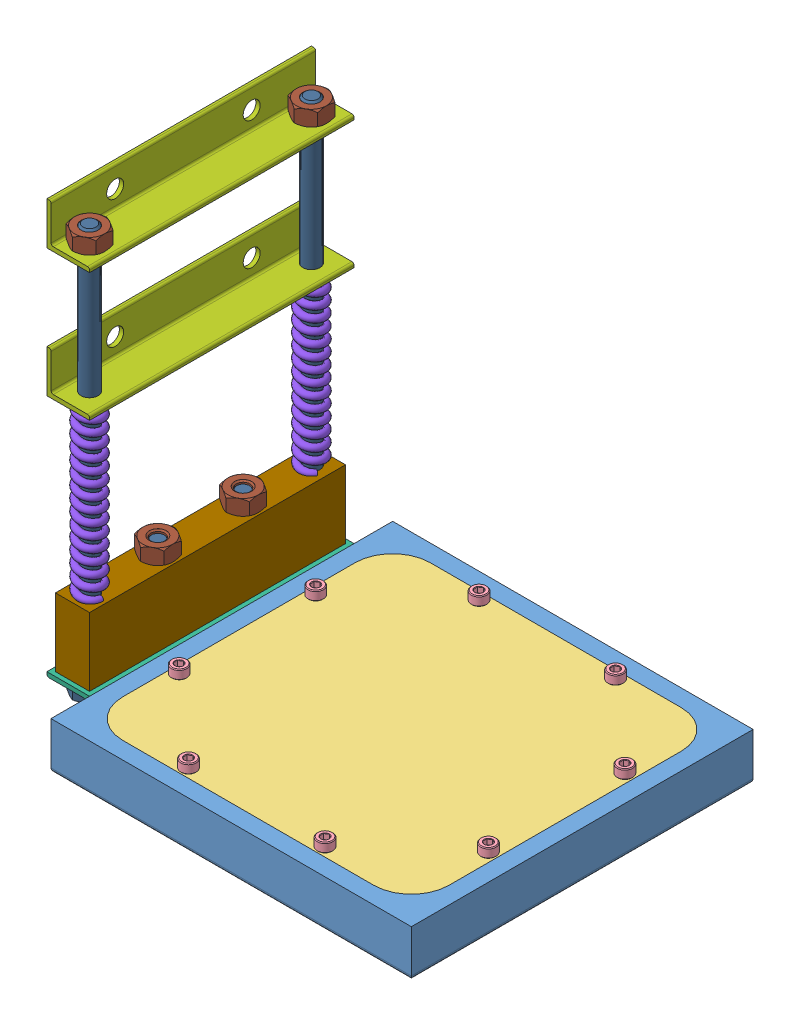
SolidWorks assembly SensorAssembly.1.11.2021, configuration Default. Lengths in mm.
Overall size (150.39 309.5 174.45).
28 component instances, 11 part files, 48 mates.
Components (placement in the parent):
- NDE Sensor Mount Assembly-2: NDE Sensor Mount Assembly [Default] at (58.3304 -65.2661 8.9552) size (134.11 22.72 127.15)
  - CaseBody-1: CaseBody [Default] at origin size (134.11 17.46 127.15)
  - WearPlateAndMount-1: WearPlateAndMount [Default] at (0 3.175 0) size (108.71 3.17 101.75)
  - Cover Plate-1: Cover Plate [Default] at (0 15.875 0) size (121.41 3.17 114.45)
  - 97334A146_NYLON SOCKET HEAD CAP SCREW-1: 97334A146_NYLON SOCKET HEAD CAP SCREW [97334A146] at (-57.531 9.525 -25.4) x (1 0 0) z (0 -1 0) size (5.74 5.74 13.88)
  - 97334A146_NYLON SOCKET HEAD CAP SCREW-2: 97334A146_NYLON SOCKET HEAD CAP SCREW [97334A146] at (-57.531 9.525 25.4) x (1 0 0) z (0 -1 0) size (5.74 5.74 13.88)
  - 97334A146_NYLON SOCKET HEAD CAP SCREW-3: 97334A146_NYLON SOCKET HEAD CAP SCREW [97334A146] at (-25.4 9.525 54.0512) x (1 0 0) z (0 -1 0) size (5.74 5.74 13.88)
  - 97334A146_NYLON SOCKET HEAD CAP SCREW-4: 97334A146_NYLON SOCKET HEAD CAP SCREW [97334A146] at (-25.4 9.525 -54.0512) x (1 0 0) z (0 -1 0) size (5.74 5.74 13.88)
  - 97334A146_NYLON SOCKET HEAD CAP SCREW-5: 97334A146_NYLON SOCKET HEAD CAP SCREW [97334A146] at (25.4 9.525 -54.0512) x (1 0 0) z (0 -1 0) size (5.74 5.74 13.88)
  - 97334A146_NYLON SOCKET HEAD CAP SCREW-6: 97334A146_NYLON SOCKET HEAD CAP SCREW [97334A146] at (25.4 9.525 54.0512) x (1 0 0) z (0 -1 0) size (5.74 5.74 13.88)
  - 97334A146_NYLON SOCKET HEAD CAP SCREW-7: 97334A146_NYLON SOCKET HEAD CAP SCREW [97334A146] at (57.531 9.525 -25.4) x (1 0 0) z (0 -1 0) size (5.74 5.74 13.88)
  - 97334A146_NYLON SOCKET HEAD CAP SCREW-8: 97334A146_NYLON SOCKET HEAD CAP SCREW [97334A146] at (57.531 9.525 25.4) x (1 0 0) z (0 -1 0) size (5.74 5.74 13.88)
- 97164A111_TAPEARED HEAT-SET INSERTS FOR PLASTIC -3: 97164A111_TAPEARED HEAT-SET INSERTS FOR PLASTIC  [97164A111] at (-4.9156 -54.1536 39.1177) x (0 -0.854491 0.519466) z (0 -0.519466 -0.854491) size (5.6 7.12 5.61)
- 97164A111_TAPEARED HEAT-SET INSERTS FOR PLASTIC -4: 97164A111_TAPEARED HEAT-SET INSERTS FOR PLASTIC  [97164A111] at (-4.9156 -54.1536 -21.2073) x (0 -0.749124 0.66243) z (0 -0.66243 -0.749124) size (5.6 7.12 5.61)
- 8982K511_MULTIPURPOSE 6061 ALUMINUM 90 DEGREE ANGLE (1) - Copy-4: 8982K511_MULTIPURPOSE 6061 ALUMINUM 90 DEGREE ANGLE (1) - Copy [8982K511] at (-8.7256 -54.1536 8.9552) x (0 1 0) z (0 0 1) size (15.88 15.88 98.42)
- DrillPressMountingAngles-1: DrillPressMountingAngles [8982K511] at (-16.6631 90.3089 8.9552) x (-1 0 0) z (0 0 -1) size (15.88 15.88 98.42)
- DrillPressMountingAngles-2: DrillPressMountingAngles [8982K511] at (-16.6631 42.6839 8.9552) x (-1 0 0) z (0 0 -1) size (15.88 15.88 98.42)
- Rudimentary Spring Sensor-1: Rudimentary Spring Sensor [Default] at (-16.6631 -20.9854 50.2302) x (-0.707107 0 0.707107) z (-0.707107 0 -0.707107) size (10.85 67.21 10.85)
- Rudimentary Spring Sensor-2: Rudimentary Spring Sensor [Default] at (-16.6631 -20.9854 -32.3198) x (-0.954285 0 0.298897) z (-0.298897 0 -0.954285) size (10.85 67.21 10.85)
- Spring STraightener-1: Spring STraightener [Default] at (-16.6631 -46.2161 8.9552) x (0 0 -1) z (1 0 0) size (95.25 25.4 12.7)
- hex bolt_ai-1: hex bolt_ai [HBOLT 0.2500-20x1.25x0.75-N] at (-16.6631 -52.5788 24.8302) x (0 1 0) z (1 0 0) size (36.53 12.85 11.13)
- hex bolt_ai-2: hex bolt_ai [HBOLT 0.2500-20x1.25x0.75-N] at (-16.6631 -52.5788 -6.9198) x (0 1 0) z (1 0 0) size (36.53 12.85 11.13)
- hex nut_ai-1: hex nut_ai [HNUT 0.2500-20-D-N] at (-16.6631 -20.8161 -6.9198) x (1 0 0) z (0 -1 0) size (11.11 12.83 5.74)
- hex nut_ai-2: hex nut_ai [HNUT 0.2500-20-D-N] at (-16.6631 -20.8161 24.8302) x (1 0 0) z (0 -1 0) size (11.11 12.83 5.74)
- hex nut_ai-3: hex nut_ai [HNUT 0.2500-20-D-N] at (-16.6631 91.8964 -32.3198) x (1 0 0) z (0 -1 0) size (11.11 12.83 5.74)
- hex nut_ai-4: hex nut_ai [HNUT 0.2500-20-D-N] at (-16.6631 91.8964 50.2302) x (1 0 0) z (0 -1 0) size (11.11 12.83 5.74)
- hex bolt_ai-3: hex bolt_ai [HBOLT 0.2500-20x5.75x0.75-N] at (-16.6631 -52.5788 -32.3198) x (0 1 0) z (-0.5 0 0.866025) size (150.83 12.85 11.13)
- hex bolt_ai-4: hex bolt_ai [HBOLT 0.2500-20x5.75x0.75-N] at (-16.6631 -52.5788 50.2302) x (0 1 0) z (-0.5 0 0.866025) size (150.83 12.85 11.13)
Mates (geometry in assembly coordinates):
- Coincident33: coincident aligned: plane of NDE Sensor Mount Assembly-2/CaseBody-1 through (58.3304 -46.2161 8.9552) normal (0 1 0); plane of 8982K511_MULTIPURPOSE 6061 ALUMINUM 90 DEGREE ANGLE (1) - Copy-4 through (-8.7256 -46.2161 58.1677) normal (0 1 0)
- Parallel1: parallel aligned: plane of DrillPressMountingAngles-1 through (-8.7256 90.3089 -40.2573) normal (0 -1 0); plane of DrillPressMountingAngles-2 through (-8.7256 42.6839 -40.2573) normal (0 -1 0)
- Distance2: distance = 88.9 mm anti-aligned: plane of DrillPressMountingAngles-2 through (-8.7256 42.6839 -40.2573) normal (0 -1 0); plane of NDE Sensor Mount Assembly-2/CaseBody-1 through (58.3304 -46.2161 8.9552) normal (0 1 0)
- Coincident36: coincident anti-aligned: plane of NDE Sensor Mount Assembly-2/CaseBody-1 through (-8.7256 -49.3911 8.9552) normal (-1 0 0); plane of 8982K511_MULTIPURPOSE 6061 ALUMINUM 90 DEGREE ANGLE (1) - Copy-4 through (-8.7256 -62.0911 58.1677) normal (1 0 0)
- Coincident37: coincident aligned: plane of 8982K511_MULTIPURPOSE 6061 ALUMINUM 90 DEGREE ANGLE (1) - Copy-4 through (-24.6006 -47.0098 58.1677) normal (-1 0 0); plane of DrillPressMountingAngles-2 through (-24.6006 42.6839 -40.2573) normal (-1 0 0)
- Coincident38: coincident aligned: plane of DrillPressMountingAngles-1 through (-24.6006 90.3089 -40.2573) normal (-1 0 0); plane of DrillPressMountingAngles-2 through (-24.6006 42.6839 -40.2573) normal (-1 0 0)
- Width1: width aligned: plane of 8982K511_MULTIPURPOSE 6061 ALUMINUM 90 DEGREE ANGLE (1) - Copy-4 through (-23.8068 -47.0098 -40.2573) normal (0 0 -1); plane of 8982K511_MULTIPURPOSE 6061 ALUMINUM 90 DEGREE ANGLE (1) - Copy-4 through (-23.8068 -47.0098 58.1677) normal (0 0 1); plane of DrillPressMountingAngles-2 through (-23.8068 57.7652 -40.2573) normal (0 0 -1); plane of DrillPressMountingAngles-2 through (-23.8068 57.7652 58.1677) normal (0 0 1)
- Coincident39: coincident aligned: plane of DrillPressMountingAngles-1 through (-23.8068 105.3902 -40.2573) normal (0 0 -1); plane of DrillPressMountingAngles-2 through (-23.8068 57.7652 -40.2573) normal (0 0 -1)
- Concentric11: concentric anti-aligned: cylinder of DrillPressMountingAngles-2 through (-16.6631 58.5599 50.2302) axis (0 -1 0) radius 3.175; cylinder of Rudimentary Spring Sensor-1 through (-16.6631 -23.4907 50.2302) axis (0 1 0) radius 3.175
- Concentric12: concentric anti-aligned: cylinder of DrillPressMountingAngles-2 through (-16.6631 58.5599 -32.3198) axis (0 -1 0) radius 3.175; cylinder of Rudimentary Spring Sensor-2 through (-16.6631 -23.4907 -32.3198) axis (0 1 0) radius 3.175
- Coincident42: coincident anti-aligned: plane of 8982K511_MULTIPURPOSE 6061 ALUMINUM 90 DEGREE ANGLE (1) - Copy-4 through (-8.7256 -46.2161 58.1677) normal (0 1 0); plane of Spring STraightener-1 through (-16.6631 -46.2161 8.9552) normal (0 -1 0)
- Concentric13: concentric anti-aligned: cylinder of 8982K511_MULTIPURPOSE 6061 ALUMINUM 90 DEGREE ANGLE (1) - Copy-4 through (-16.6631 -62.0911 50.2302) axis (0 1 0) radius 3.175; cylinder of Spring STraightener-1 through (-16.6631 -20.8161 50.2302) axis (0 -1 0) radius 3.175
- Concentric14: concentric anti-aligned: cylinder of 8982K511_MULTIPURPOSE 6061 ALUMINUM 90 DEGREE ANGLE (1) - Copy-4 through (-16.6631 -62.0911 -32.3198) axis (0 1 0) radius 3.175; cylinder of Spring STraightener-1 through (-16.6631 -20.8161 -32.3198) axis (0 -1 0) radius 3.175
- Concentric15: concentric anti-aligned: cylinder of NDE Sensor Mount Assembly-2/CaseBody-1 through (-2.3756 -54.1536 -21.2073) axis (-1 0 0) radius 2.3495; cylinder of 97164A111_TAPEARED HEAT-SET INSERTS FOR PLASTIC -4 through (-4.9156 -54.1536 -21.2073) axis (1 0 0) radius 2.0828
- Concentric16: concentric anti-aligned: cylinder of NDE Sensor Mount Assembly-2/CaseBody-1 through (-2.3756 -54.1536 39.1177) axis (-1 0 0) radius 2.3495; cylinder of 97164A111_TAPEARED HEAT-SET INSERTS FOR PLASTIC -3 through (-4.9156 -54.1536 39.1177) axis (1 0 0) radius 2.0828
- Coincident43: coincident anti-aligned: plane of NDE Sensor Mount Assembly-2/CaseBody-1 through (-2.3756 -54.1536 39.1177) normal (-1 0 0); plane of 97164A111_TAPEARED HEAT-SET INSERTS FOR PLASTIC -3 through (-2.3756 -55.9333 40.1997) normal (1 0 0)
- Coincident44: coincident anti-aligned: plane of NDE Sensor Mount Assembly-2/CaseBody-1 through (-2.3756 -54.1536 -21.2073) normal (-1 0 0); plane of 97164A111_TAPEARED HEAT-SET INSERTS FOR PLASTIC -4 through (-2.3756 -55.7138 -19.8275) normal (1 0 0)
- Concentric17: concentric aligned: cylinder of Spring STraightener-1 through (-16.6631 -20.8161 24.8302) axis (0 -1 0) radius 3.175; cylinder of hex bolt_ai-1 through (-16.6631 -52.5788 24.8302) axis (0 -1 0) radius 3.175
- Concentric18: concentric aligned: cylinder of Spring STraightener-1 through (-16.6631 -20.8161 -6.9198) axis (0 -1 0) radius 3.175; cylinder of hex bolt_ai-2 through (-16.6631 -52.5788 -6.9198) axis (0 -1 0) radius 3.175
- Coincident45: coincident anti-aligned: plane of 8982K511_MULTIPURPOSE 6061 ALUMINUM 90 DEGREE ANGLE (1) - Copy-4 through (-23.8068 -47.8036 58.1677) normal (0 -1 0); plane of hex bolt_ai-2 through (-16.6631 -47.8036 -0.4966) normal (0 1 0)
- Coincident46: coincident anti-aligned: plane of 8982K511_MULTIPURPOSE 6061 ALUMINUM 90 DEGREE ANGLE (1) - Copy-4 through (-23.8068 -47.8036 58.1677) normal (0 -1 0); plane of hex bolt_ai-1 through (-16.6631 -47.8036 31.2534) normal (0 1 0)
- Coincident47: coincident aligned: plane of hex bolt_ai-1 through (-22.2257 -47.8036 28.0418) normal (-1 0 0); plane of hex bolt_ai-2 through (-22.2257 -47.8036 -3.7082) normal (-1 0 0)
- Coincident48: coincident anti-aligned: plane of Spring STraightener-1 through (-16.6631 -20.8161 8.9552) normal (0 1 0); plane of hex nut_ai-1 through (-16.6631 -20.8161 -0.5039) normal (0 -1 0)
- Concentric19: concentric aligned: cylinder of hex bolt_ai-2 through (-16.6631 -52.5788 -6.9198) axis (0 -1 0) radius 3.175; cylinder of hex nut_ai-1 through (-16.6631 -15.0757 -6.9198) axis (0 -1 0) radius 2.5527
- Concentric20: concentric aligned: cylinder of hex bolt_ai-1 through (-16.6631 -52.5788 24.8302) axis (0 -1 0) radius 3.175; cylinder of hex nut_ai-2 through (-16.6631 -15.0757 24.8302) axis (0 -1 0) radius 2.5527
- Coincident49: coincident aligned: plane of hex nut_ai-1 through (-16.6631 -15.0757 -0.5039) normal (0 1 0); plane of hex nut_ai-2 through (-16.6631 -15.0757 31.2461) normal (0 1 0)
- Coincident50: coincident aligned: plane of hex nut_ai-1 through (-22.2193 -15.0757 -3.7118) normal (-1 0 0); plane of hex nut_ai-2 through (-22.2193 -15.0757 28.0382) normal (-1 0 0)
- Concentric21: concentric aligned: cylinder of Spring STraightener-1 through (-16.6631 -20.8161 -32.3198) axis (0 -1 0) radius 3.175; cylinder of hex bolt_ai-3 through (-16.6631 -52.5788 -32.3198) axis (0 -1 0) radius 3.175
- Coincident51: coincident anti-aligned: plane of 8982K511_MULTIPURPOSE 6061 ALUMINUM 90 DEGREE ANGLE (1) - Copy-4 through (-23.8068 -47.8036 58.1677) normal (0 -1 0); plane of hex bolt_ai-3 through (-22.2257 -47.8036 -35.5313) normal (0 1 0)
- Concentric22: concentric aligned: cylinder of Spring STraightener-1 through (-16.6631 -20.8161 50.2302) axis (0 -1 0) radius 3.175; cylinder of hex bolt_ai-4 through (-16.6631 -52.5788 50.2302) axis (0 -1 0) radius 3.175
- Coincident52: coincident anti-aligned: plane of 8982K511_MULTIPURPOSE 6061 ALUMINUM 90 DEGREE ANGLE (1) - Copy-4 through (-23.8068 -47.8036 58.1677) normal (0 -1 0); plane of hex bolt_ai-4 through (-22.2257 -47.8036 47.0187) normal (0 1 0)
- Coincident53: coincident aligned: plane of hex bolt_ai-3 through (-22.2257 -47.8036 -35.5313) normal (-1 0 0); plane of hex bolt_ai-4 through (-22.2257 -47.8036 47.0187) normal (-1 0 0)
- Concentric23: concentric aligned: cylinder of hex nut_ai-4 through (-16.6631 97.6368 50.2302) axis (0 -1 0) radius 2.5527; cylinder of hex bolt_ai-4 through (-16.6631 -52.5788 50.2302) axis (0 -1 0) radius 3.175
- Distance3: distance = 0.6096 mm aligned: plane of hex nut_ai-4 through (-16.6631 97.6368 56.6461) normal (0 1 0); plane of hex bolt_ai-4 through (-16.6631 98.2464 50.2302) normal (0 1 0)
- Coincident55: coincident aligned: plane of hex nut_ai-3 through (-16.6631 97.6368 -25.9039) normal (0 1 0); plane of hex nut_ai-4 through (-16.6631 97.6368 56.6461) normal (0 1 0)
- Concentric24: concentric aligned: cylinder of hex nut_ai-3 through (-16.6631 97.6368 -32.3198) axis (0 -1 0) radius 2.5527; cylinder of hex bolt_ai-3 through (-16.6631 -52.5788 -32.3198) axis (0 -1 0) radius 3.175
- Coincident56: coincident aligned: plane of hex nut_ai-3 through (-11.1068 97.6368 -29.1118) normal (1 0 0); plane of hex nut_ai-4 through (-11.1068 97.6368 53.4382) normal (1 0 0)
- Distance4: distance = 63.5 mm anti-aligned: plane of DrillPressMountingAngles-2 through (-8.7256 42.6839 -42.0824) normal (0 -1 0); plane of NDE Sensor Mount Assembly-2/CaseBody-1 through (58.3304 -46.2161 8.9552) normal (0 1 0)
- Coincident57: coincident aligned: plane of Rudimentary Spring Sensor-1 through (-20.0411 42.6839 39.0128) normal (0 1 0); plane of Rudimentary Spring Sensor-2 through (-27.8649 17.2839 -35.5674) normal (0 1 0)
- Coincident58: coincident anti-aligned: plane of DrillPressMountingAngles-2 through (-8.7256 17.2839 -40.3335) normal (0 -1 0); plane of Rudimentary Spring Sensor-1 through (-20.0411 42.6839 39.0128) normal (0 1 0)
- Coincident59: coincident aligned: plane of Rudimentary Spring Sensor-1 through (-16.6631 42.6836 54.1228) normal (-0.995019 0.09969 0); plane of Rudimentary Spring Sensor-2 through (-16.6631 17.2836 -28.4272) normal (-0.995019 0.09969 0)
- Distance5: distance = 46.0375 mm anti-aligned: plane of DrillPressMountingAngles-1 through (-8.7256 90.3089 -40.2573) normal (0 -1 0); plane of DrillPressMountingAngles-2 through (-22.2193 44.2714 -40.2573) normal (0 1 0)
- Distance6: distance = 125.3864 mm: plane of assembly through (0 0 0) normal (1 0 0); plane of assembly; plane of NDE Sensor Mount Assembly-2/CaseBody-1 through (125.3864 -49.3911 8.9552) normal (1 0 0)
- Distance7: distance = 54.621 mm anti-aligned: plane of NDE Sensor Mount Assembly-2/CaseBody-1 through (58.3304 -49.3911 -54.621) normal (0 0 -1)
- Distance8: distance = 39.8661 mm: plane of assembly through (0 0 0) normal (0 1 0); plane of assembly; plane of NDE Sensor Mount Assembly-2/WearPlateAndMount-1 through (58.3304 -65.2661 8.9552) normal (0 -1 0)
- Coincident60: coincident anti-aligned: plane of DrillPressMountingAngles-2 through (-8.7256 42.6839 -40.2573) normal (0 -1 0); plane of Rudimentary Spring Sensor-2 through (-33.8116 42.6839 -21.2652) normal (0 1 0)
- Coincident61: coincident anti-aligned: plane of DrillPressMountingAngles-2 through (-8.7256 42.6839 -40.2573) normal (0 -1 0); plane of Rudimentary Spring Sensor-1 through (-26.7359 42.6839 67.9732) normal (0 1 0)
- Width2: width aligned: plane of NDE Sensor Mount Assembly-2/CaseBody-1 through (58.3304 -49.3911 -54.621) normal (0 0 -1); plane of NDE Sensor Mount Assembly-2/CaseBody-1 through (58.3304 -49.3911 72.5314) normal (0 0 1); plane of 8982K511_MULTIPURPOSE 6061 ALUMINUM 90 DEGREE ANGLE (1) - Copy-4 through (-23.8068 -47.0098 -40.2573) normal (0 0 -1); plane of 8982K511_MULTIPURPOSE 6061 ALUMINUM 90 DEGREE ANGLE (1) - Copy-4 through (-23.8068 -47.0098 58.1677) normal (0 0 1)
